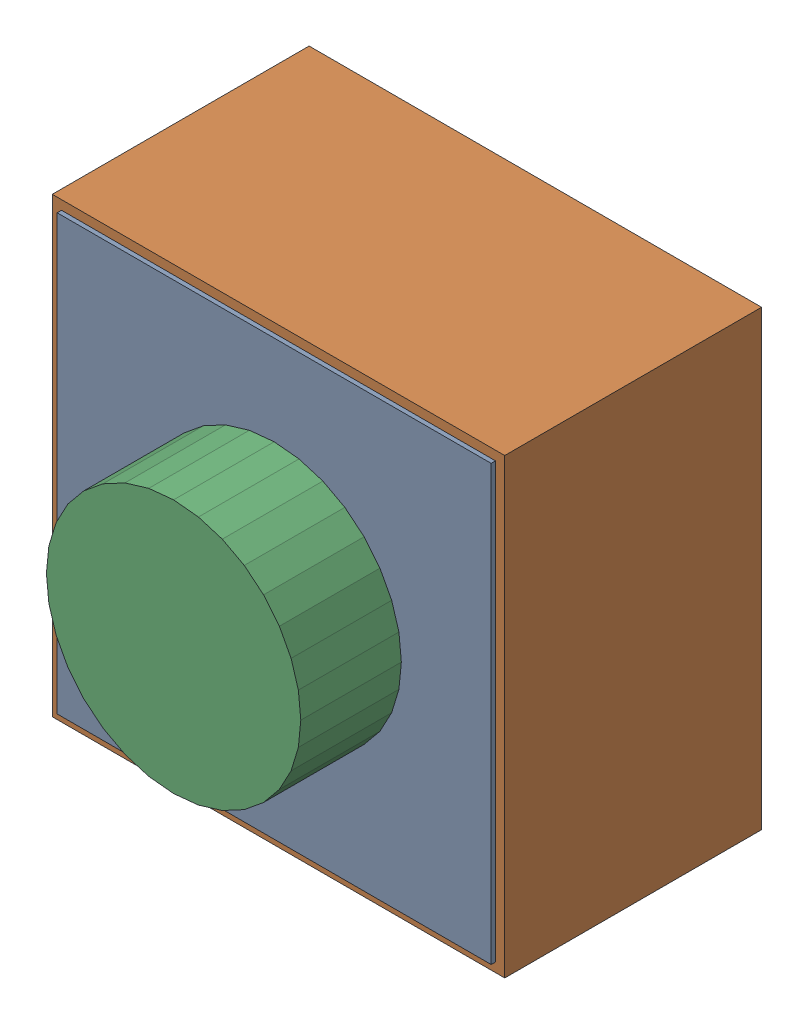
SolidWorks assembly RESET, configuration Default. Lengths in mm.
Overall size (6.25 6.25 5).
6 component instances, 3 part files, 0 mates.
Components (placement in the parent):
- 506290208-1: 506290208 [Default] at (214.63 168.91 0.0127) size (6 6 3.61)
  - Extruded_6-1: Extruded_6 [Default] at origin size (6 6 3.61)
- 506290464-1: 506290464 [Default] at (214.63 168.91 0.0127) size (6.25 6.25 3.55)
  - Extruded_7-1: Extruded_7 [Default] at origin size (6.25 6.25 3.55)
- 506291104-1: 506291104 [Default] at (214.63 168.91 0.0127) size (3.52 3.52 5)
  - Extruded_8-1: Extruded_8 [Default] at origin size (3.52 3.52 5)
